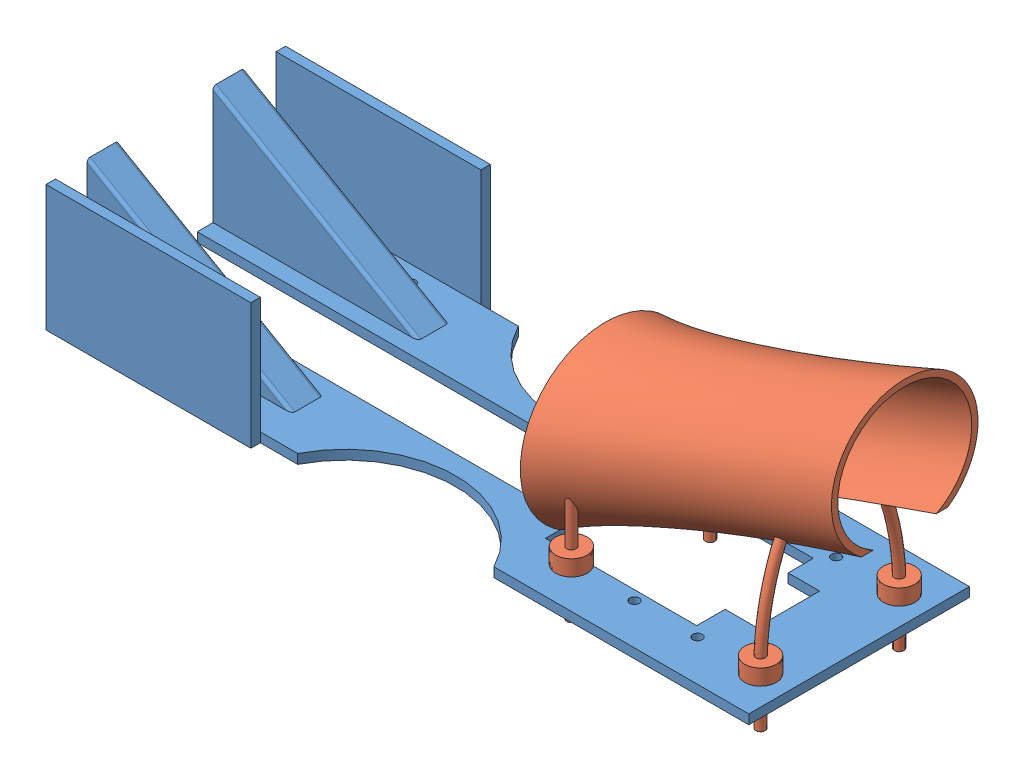
SolidWorks assembly 装配体1(1), configuration 默认. Lengths in mm.
Overall size (245 98.68 188.9).
2 component instances, 2 part files, 3 mates.
Components (placement in the parent):
- 出射轨道底板3.0-1: 出射轨道底板3.0 [默认] at (-54.2645 -39.8079 223.9082) size (230.25 47.86 188.9)
- 乒乓球轨道-1: 乒乓球轨道 [默认] at (2.517 -13.8979 223.9082) x (0 0 -1) z (1 0 0) size (59.58 98.68 97.34)
Mates (geometry in assembly coordinates):
- 重合1: coincident: plane of 出射轨道底板3.0-1 through (-54.2645 -36.8079 223.9082) normal (0 1 0); plane of 乒乓球轨道-1 through (73.767 -36.8079 201.9082) normal (0 -1 0)
- 同心1: concentric: circle of 出射轨道底板3.0-1; circle of 乒乓球轨道-1
- 同心2: concentric aligned: circle of 出射轨道底板3.0-1; circle of 乒乓球轨道-1
